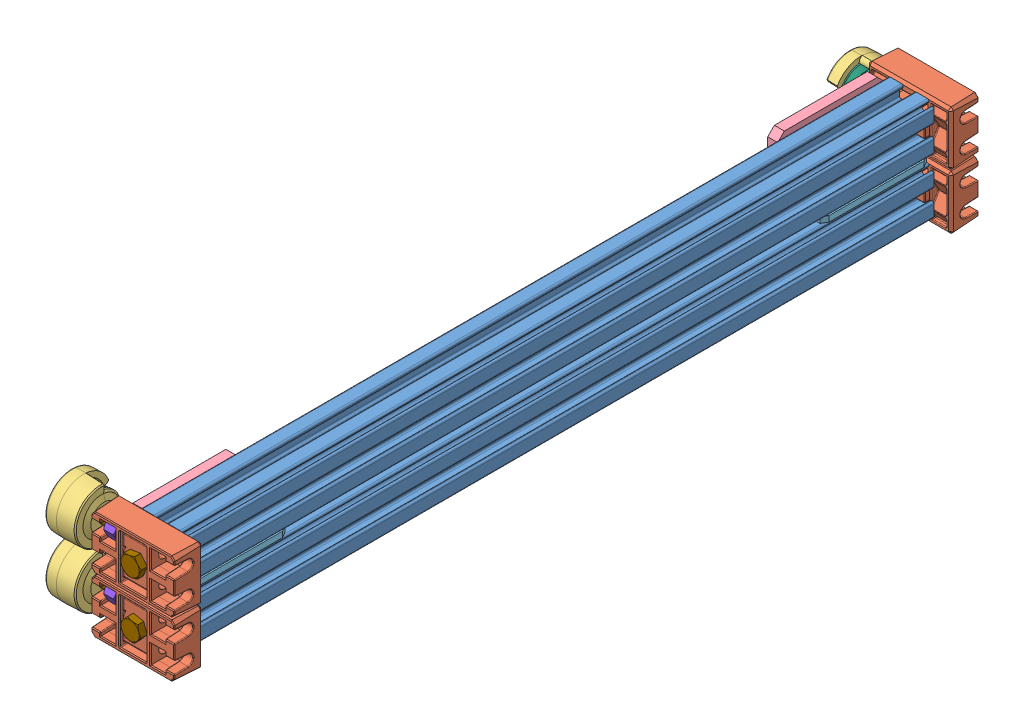
SolidWorks assembly REV-45-1507.STEP, configuration Default. Lengths in mm.
Overall size (35.03 42.55 251.85).
48 component instances, 11 part files, 0 mates.
Components (placement in the parent):
- single stage.STEP-1: single stage.STEP [Default] at origin size (35.03 35.21 251.41)
  - REV-41-1431.STEP-1: REV-41-1431.STEP [Default] at origin size (15 15 225)
  - REV-41-1511 V2.STEP-1: REV-41-1511 V2.STEP [Default] at (0 0 225) x (1 0 0) z (0 -1 0) size (25.27 10 16.27)
  - REV-41-1512 V2.STEP-1: REV-41-1512 V2.STEP [Default] at (-13.3855 4 229.5) x (0 -0.999636 0.026991) z (-1 0 0) size (16.25 15.38 9.77)
  - REV-41-1519.STEP-1: REV-41-1519.STEP [Default] at (-8.6 16.85 209) x (-1 0 0) z (0 0 1) size (7.02 29.79 32.41)
  - REV-41-1520.STEP-1: REV-41-1520.STEP [Default] at (0 8.35 209) x (0 -1 0) z (0 0 1) size (9.73 12.5 32.41)
  - REV-41-1511 V2.STEP-2: REV-41-1511 V2.STEP [Default] x (1 0 0) z (0 1 0) size (25.27 10 16.27)
  - REV-41-1512 V2.STEP-2: REV-41-1512 V2.STEP [Default] at (-13.3855 -4 -4.5) x (0 0.994583 -0.103946) z (-1 0 0) size (16.25 15.38 9.77)
  - REV-41-1368.STEP-1: REV-41-1368.STEP [Default] at (-17.6355 -4 -4.5) x (0 -0.999129 0.041719) z (0 0.041719 0.999129) size (12.02 4 12.02)
  - REV-41-1368.STEP-2: REV-41-1368.STEP [Default] at (-17.6355 4 229.5) x (0 -0.657313 0.753618) z (0 0.753618 0.657313) size (12.02 4 12.02)
- single stage.STEP-2: single stage.STEP [Default] at (0 16.7 225) x (1 0 0) z (0 0 -1) size (35.03 35.21 251.41)
  - REV-41-1431.STEP-1: REV-41-1431.STEP [Default] at origin size (15 15 225)
  - REV-41-1511 V2.STEP-1: REV-41-1511 V2.STEP [Default] at (0 0 225) x (1 0 0) z (0 -1 0) size (25.27 10 16.27)
  - REV-41-1512 V2.STEP-1: REV-41-1512 V2.STEP [Default] at (-13.3855 4 229.5) x (0 -0.999636 0.026991) z (-1 0 0) size (16.25 15.38 9.77)
  - REV-41-1519.STEP-1: REV-41-1519.STEP [Default] at (-8.6 16.85 209) x (-1 0 0) z (0 0 1) size (7.02 29.79 32.41)
  - REV-41-1520.STEP-1: REV-41-1520.STEP [Default] at (0 8.35 209) x (0 -1 0) z (0 0 1) size (9.73 12.5 32.41)
  - REV-41-1511 V2.STEP-2: REV-41-1511 V2.STEP [Default] x (1 0 0) z (0 1 0) size (25.27 10 16.27)
  - REV-41-1512 V2.STEP-2: REV-41-1512 V2.STEP [Default] at (-13.3855 -4 -4.5) x (0 0.994583 -0.103946) z (-1 0 0) size (16.25 15.38 9.77)
  - REV-41-1368.STEP-1: REV-41-1368.STEP [Default] at (-17.6355 -4 -4.5) x (0 -0.999129 0.041719) z (0 0.041719 0.999129) size (12.02 4 12.02)
  - REV-41-1368.STEP-2: REV-41-1368.STEP [Default] at (-17.6355 4 229.5) x (0 -0.657313 0.753618) z (0 0.753618 0.657313) size (12.02 4 12.02)
- REV-41-1359 Simple.STEP-1: REV-41-1359 Simple.STEP [Default] at (-4.3 16.7 8) x (0 -0.430498 -0.902592) z (0 0.902592 -0.430498) size (6.36 10.01 6.36)
- REV-41-1361 Simple.STEP-1: REV-41-1361 Simple.STEP [Default] at (-10.5 16.7 8) x (0 -0.445235 -0.895414) z (0 0.895414 -0.445235) size (5.94 4.01 6.36)
- REV-41-1359 Simple.STEP-2: REV-41-1359 Simple.STEP [Default] at (-4.3 16.7 24) x (0 -0.580691 -0.814124) z (0 0.814124 -0.580691) size (6.36 10.01 6.36)
- REV-41-1361 Simple.STEP-2: REV-41-1361 Simple.STEP [Default] at (-10.5 16.7 24) x (0 -0.593958 -0.804496) z (0 0.804496 -0.593958) size (5.94 4.01 6.36)
- REV-41-1359 Simple.STEP-3: REV-41-1359 Simple.STEP [Default] at (-4.3 0 201) x (0 -0.71324 -0.70092) z (0 0.70092 -0.71324) size (6.36 10.01 6.36)
- REV-41-1361 Simple.STEP-3: REV-41-1361 Simple.STEP [Default] at (-10.5 0 201) x (0 -0.724633 -0.689135) z (0 0.689135 -0.724633) size (5.94 4.01 6.36)
- REV-41-1359 Simple.STEP-4: REV-41-1359 Simple.STEP [Default] at (-4.3 0 217) x (0 -0.824118 -0.566419) z (0 0.566419 -0.824118) size (6.36 10.01 6.36)
- REV-41-1361 Simple.STEP-4: REV-41-1361 Simple.STEP [Default] at (-10.5 0 217) x (0 -0.833292 -0.552834) z (0 0.552834 -0.833292) size (5.94 4.01 6.36)
- REV-41-1360 Simple.STEP-1: REV-41-1360 Simple.STEP [Default] at (-21.6355 20.7 229.5) x (0 0.109387 0.993999) z (0 0.993999 -0.109387) size (6.36 18.01 6.36)
- REV-41-1360 Simple.STEP-2: REV-41-1360 Simple.STEP [Default] at (-21.6355 4 229.5) x (0 -0.222279 0.974983) z (0 0.974983 0.222279) size (6.36 18.01 6.36)
- REV-41-1360 Simple.STEP-3: REV-41-1360 Simple.STEP [Default] at (-21.6355 12.7 -4.5) x (0 -0.344617 0.938743) z (0 0.938743 0.344617) size (6.36 18.01 6.36)
- REV-41-1360 Simple.STEP-4: REV-41-1360 Simple.STEP [Default] at (0 16.7 -9.3) x (0.896929 0.442175 0) z (0.442175 -0.896929 0) size (6.36 18.01 6.36)
- REV-41-1360 Simple.STEP-5: REV-41-1360 Simple.STEP [Default] at (0 0 -9.3) x (0.896929 0.442175 0) z (0.442175 -0.896929 0) size (6.36 18.01 6.36)
- REV-41-1360 Simple.STEP-6: REV-41-1360 Simple.STEP [Default] at (0 16.7 234.3) x (-0.153031 0.988221 0) z (-0.988221 -0.153031 0) size (6.36 18.01 6.36)
- REV-41-1360 Simple.STEP-7: REV-41-1360 Simple.STEP [Default] at (0 0 234.3) x (-0.194189 -0.980964 0) z (0.980964 -0.194189 0) size (6.36 18.01 6.36)
- REV-41-1360 Simple.STEP-8: REV-41-1360 Simple.STEP [Default] at (-21.6355 -4 -4.5) x (0 -0.489098 0.872229) z (0 0.872229 0.489098) size (6.36 18.01 6.36)
- REV-41-1361 Simple.STEP-5: REV-41-1361 Simple.STEP [Default] at (-9.8355 -4 -4.5) x (0 0.529919 0.848048) z (0 0.848048 -0.529919) size (5.94 4.01 6.36)
- REV-41-1361 Simple.STEP-6: REV-41-1361 Simple.STEP [Default] at (-9.8355 12.7 -4.5) x (0 0.529919 0.848048) z (0 0.848048 -0.529919) size (5.94 4.01 6.36)
- REV-41-1361 Simple.STEP-7: REV-41-1361 Simple.STEP [Default] at (-9.8355 4 229.5) x (0 -0.5 -0.866025) z (0 -0.866025 0.5) size (5.94 4.01 6.36)
- REV-41-1361 Simple.STEP-8: REV-41-1361 Simple.STEP [Default] at (-9.8355 20.7 229.5) x (0 -0.5 -0.866025) z (0 -0.866025 0.5) size (5.94 4.01 6.36)
- M3 x 8mm low profile socket.STEP-1: M3 x 8mm low profile socket.STEP [Default] at (0 5.65 24) x (-0.837169 0 -0.546944) z (-0.546944 0 0.837169) size (5.4 9.8 5.4)
- hex nut style 1_am_B18.2.4.1M - Hex nut, Style 1,  M3 x 0.5 --D-N.STEP-1: hex nut style 1_am_B18.2.4.1M - Hex nut, Style 1,  M3 x 0.5 --D-N.STEP [Default] at (0 13.2 24) x (0.5 0 -0.866025) z (0 1 0) size (6.36 6.36 2.41)
- M3 x 8mm low profile socket.STEP-2: M3 x 8mm low profile socket.STEP [Default] at (0 5.65 8) x (-0.925243 0 -0.379375) z (-0.379375 0 0.925243) size (5.4 9.8 5.4)
- hex nut style 1_am_B18.2.4.1M - Hex nut, Style 1,  M3 x 0.5 --D-N.STEP-2: hex nut style 1_am_B18.2.4.1M - Hex nut, Style 1,  M3 x 0.5 --D-N.STEP [Default] at (0 13.2 8) x (1 0 0) z (0 1 0) size (6.36 6.36 2.41)
- hex nut style 1_am_B18.2.4.1M - Hex nut, Style 1,  M3 x 0.5 --D-N.STEP-3: hex nut style 1_am_B18.2.4.1M - Hex nut, Style 1,  M3 x 0.5 --D-N.STEP [Default] at (0 3.5 217) x (-0.5 0 0.866025) z (0 -1 0) size (6.36 6.36 2.41)
- M3 x 8mm low profile socket.STEP-3: M3 x 8mm low profile socket.STEP [Default] at (0 11.05 217) x (-0.546944 0 -0.837169) z (0.837169 0 -0.546944) size (5.4 9.8 5.4)
- hex nut style 1_am_B18.2.4.1M - Hex nut, Style 1,  M3 x 0.5 --D-N.STEP-4: hex nut style 1_am_B18.2.4.1M - Hex nut, Style 1,  M3 x 0.5 --D-N.STEP [Default] at (0 3.5 201) x (-0.5 0 0.866025) z (0 -1 0) size (6.36 6.36 2.41)
- M3 x 8mm low profile socket.STEP-4: M3 x 8mm low profile socket.STEP [Default] at (0 11.05 201) x (-0.546944 0 -0.837169) z (0.837169 0 -0.546944) size (5.4 9.8 5.4)
